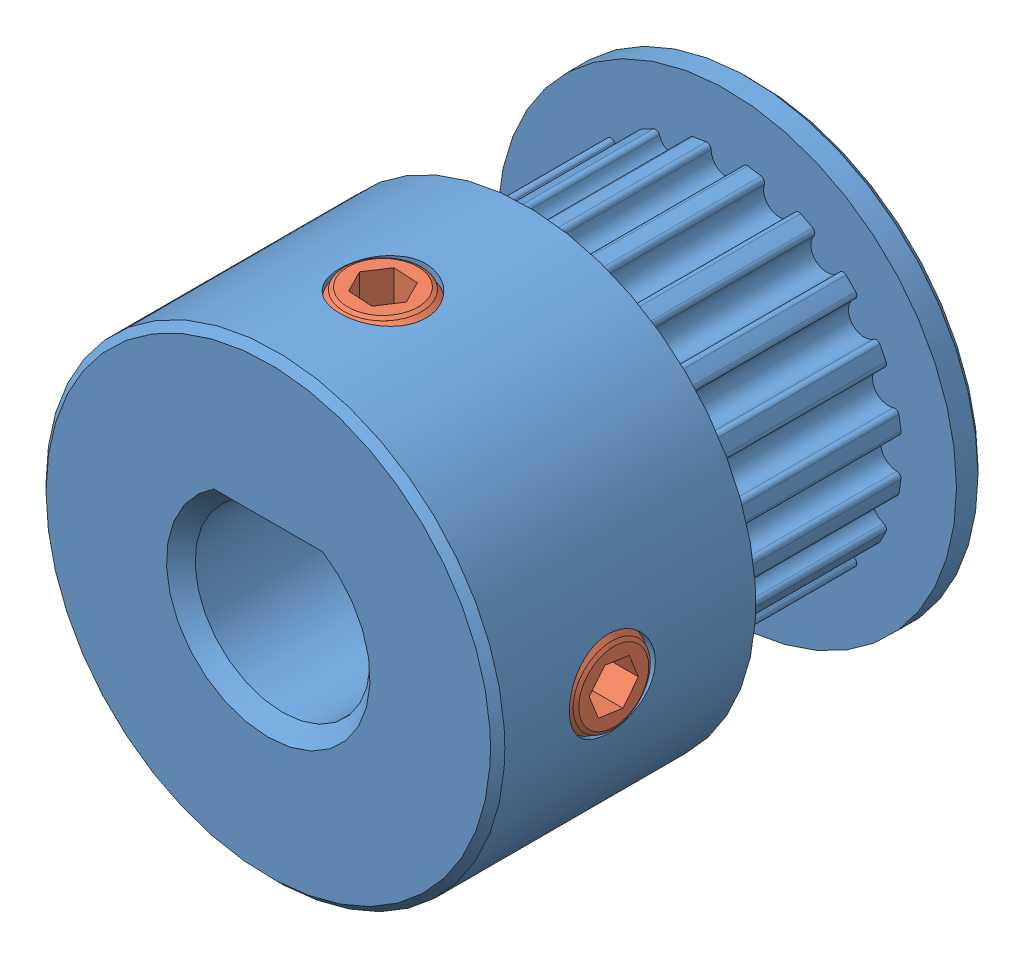
SolidWorks assembly GT2 20 Tooth Assy (ID 6mm), configuration Default. Lengths in mm.
Overall size (16.05 16.05 17).
3 component instances, 2 part files, 7 mates.
Components (placement in the parent):
- GT2 Pulley 20 Tooth (ID6mm)-1: GT2 Pulley 20 Tooth (ID6mm) [Default] at origin size (16 16 17)
- socket set screw flat point_am-2: socket set screw flat point_am [B18.3.6M - M3 x 0.5 x 5 Hex Socket Flat Pt. SS --S] at (8.05 0 12) x (-1 0 0) z (0 -0.930433 -0.366463) size (5 3 3)
- socket set screw flat point_am-3: socket set screw flat point_am [B18.3.6M - M3 x 0.5 x 5 Hex Socket Flat Pt. SS --S] at (0 8.05 12) x (0 -1 0) z (-0.546944 0 0.837169) size (5 3 3)
Mates (geometry in assembly coordinates):
- Coincident1: coincident aligned: plane of GT2 Pulley 20 Tooth (ID6mm)-1 through (0 0 0) normal (0 0 1)
- Coincident2: coincident aligned: plane of GT2 Pulley 20 Tooth (ID6mm)-1 through (0 0 0) normal (1 0 0)
- Coincident3: coincident aligned: plane of GT2 Pulley 20 Tooth (ID6mm)-1 through (0 0 0) normal (0 1 0)
- Concentric2: concentric aligned: cylinder of GT2 Pulley 20 Tooth (ID6mm)-1 through (8 0 12) axis (1 0 0) radius 1.5; cylinder of socket set screw flat point_am-2 through (20.75 0 12) axis (1 0 0) radius 1.5
- Concentric3: concentric anti-aligned: cylinder of GT2 Pulley 20 Tooth (ID6mm)-1 through (0 2.5 12) axis (0 -1 0) radius 1.5; cylinder of socket set screw flat point_am-3 through (0 20.75 12) axis (0 1 0) radius 1.5
- Tangent1: tangent anti-aligned: cylinder of GT2 Pulley 20 Tooth (ID6mm)-1 through (0 0 -1) axis (0 0 1) radius 3.05; plane of socket set screw flat point_am-2 through (3.05 0.3665 11.0696) normal (-1 0 0)
- Tangent2: tangent anti-aligned: cylinder of GT2 Pulley 20 Tooth (ID6mm)-1 through (0 0 -1) axis (0 0 1) radius 3.05; plane of socket set screw flat point_am-3 through (0.8372 3.05 12.5469) normal (0 -1 0)
